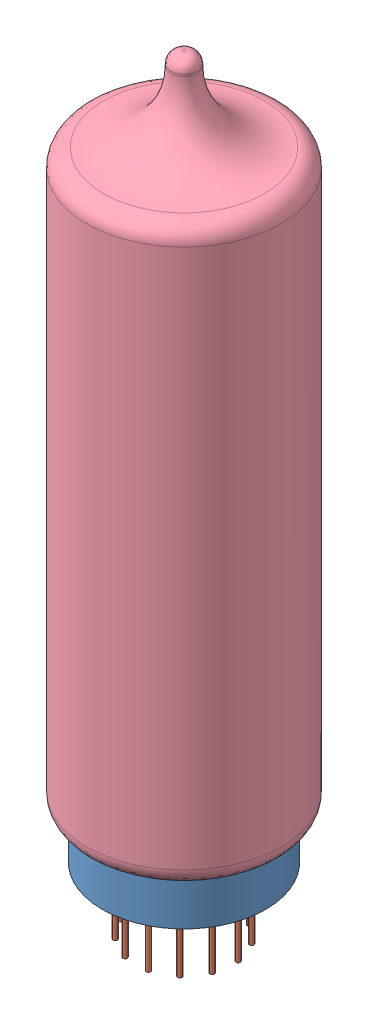
SolidWorks assembly em84, configuration Default. Lengths in mm.
Overall size (22.23 86.78 22).
4 component instances, 4 part files, 5 mates.
Components (placement in the parent):
- pcb_standoff-1: pcb_standoff [Default] at (7.1038 3.7208 15.749) size (18.5 7 18.5)
- tube_leads-1: tube_leads [Default] at (7.1038 8.4415 15.749) size (11.42 12 11.34)
- tiepian-2: tiepian [默认] at (-3.1929 44.2336 11.9251) x (0 -1 0) z (-0.94134 0 -0.337459) size (33 5 0.1)
- tube_body2-1: tube_body2 [Default] at (7.1038 8.7208 15.749) size (22 74.5 22)
Mates (geometry in assembly coordinates):
- Concentric1: concentric aligned: circle of pcb_standoff-1; circle of tube_leads-1
- Concentric3: concentric aligned: circle of pcb_standoff-1; circle of tube_leads-1
- 重合1: coincident: plane of pcb_standoff-1 through (7.1038 8.7208 15.749) normal (0 1 0); plane of tube_body2-1 through (7.1038 8.7208 15.749) normal (0 -1 0)
- 同心1: concentric anti-aligned: circle of pcb_standoff-1; circle of tube_body2-1
- 锁定1: lock: unknown of tiepian-2; unknown of tube_body2-1
